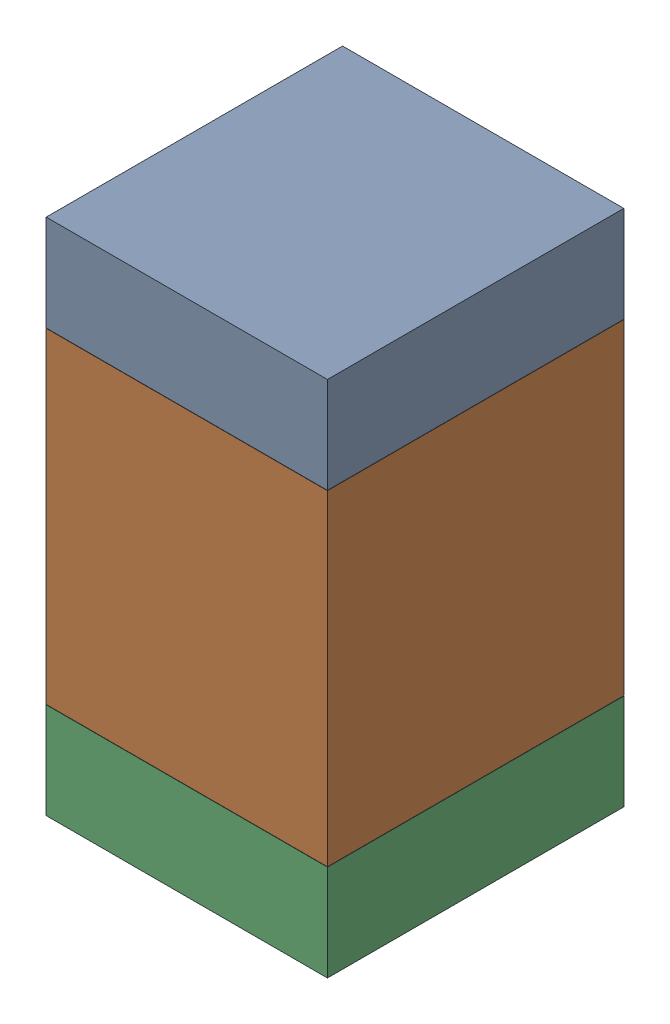
SolidWorks assembly C3, configuration Default. Lengths in mm.
Overall size (0.95 1.75 1).
6 component instances, 2 part files, 0 mates.
Components (placement in the parent):
- 6575495072-1: 6575495072 [Default] at (10.922 41.3525 0) size (0.95 0.32 1)
  - Extruded_6-1: Extruded_6 [Default] at origin size (0.95 0.32 1)
- 6575494912-1: 6575494912 [Default] at (10.922 40.64 0) size (0.95 1.1 1)
  - Extruded_7-1: Extruded_7 [Default] at origin size (0.95 1.1 1)
- 6575495072-2: 6575495072 [Default] at (10.922 39.9275 0) size (0.95 0.32 1)
  - Extruded_6-1: Extruded_6 [Default] at origin size (0.95 0.32 1)
